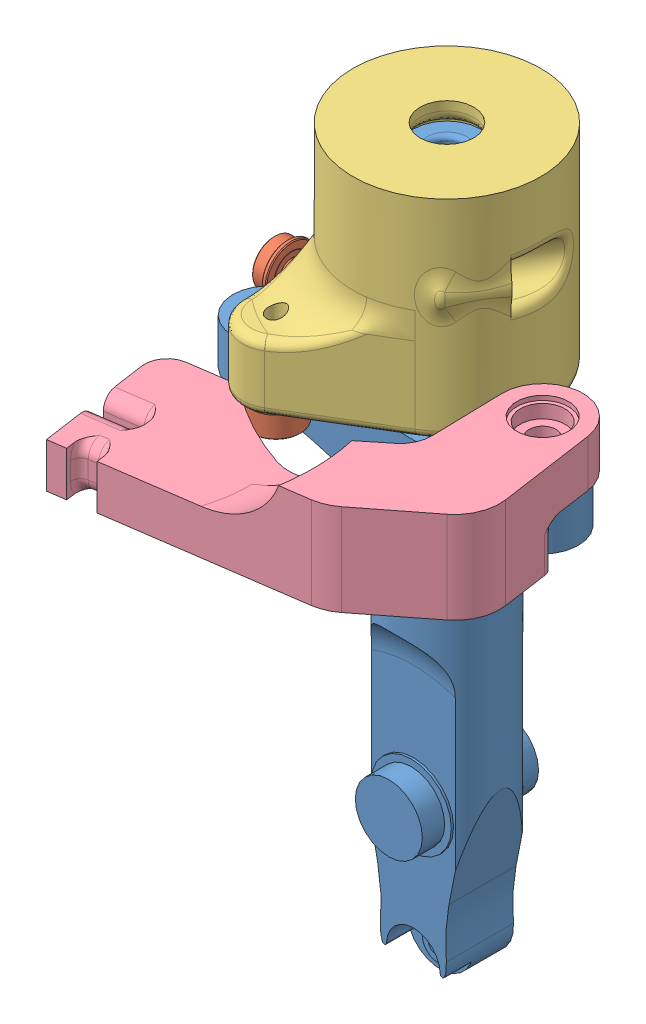
SolidWorks assembly Twist Assembly, configuration Default. Lengths in mm.
Overall size (93.92 163.27 87.75).
6 component instances, 4 part files, 9 mates.
Components (placement in the parent):
- Center Core-1: Center Core [Default] at (54.6829 0.4062 116.0872) size (77.28 158.27 34.47)
- Bearing-1: Bearing [685] at (40.6829 113.6785 140.3359) x (0 -1 0) z (-0.553847 0 0.832618) size (5 11 11)
- Twist-1: Twist [Default] at (54.6829 116.6785 116.0872) x (0.866025 0 0.5) z (-0.5 0 0.866025) size (43.41 47 56.5)
- Bearing-2: Bearing [6804] at (54.6829 120.1785 116.0872) x (0 1 0) z (0 0 1) size (7 32 32)
- CAM Twist-1: CAM Twist [Default] at (85.3215 126.6785 125.3217) x (0.989772 0 -0.142661) z (-0.142661 0 -0.989772) size (76.94 21.7 49.19)
- Bearing-3: Bearing [MF105] at (8.0433 107.4625 106.1073) size (4 11.6 11.6)
Mates (geometry in assembly coordinates):
- Concentric1: concentric anti-aligned: cylinder of Center Core-1 through (54.6829 89.2322 116.0872) axis (0 1 0) radius 10; cylinder of Bearing-2 through (54.6829 110.5999 116.0872) axis (0 -1 0) radius 10
- Coincident1: coincident anti-aligned: plane of Center Core-1 through (54.6829 116.6785 126.0872) normal (0 1 0); plane of Bearing-2 through (43.2829 116.6785 116.0872) normal (0 -1 0)
- Concentric2: concentric anti-aligned: cylinder of Center Core-1 through (54.6829 93.6785 116.0872) axis (0 1 0) radius 17.2345; cylinder of Twist-1 through (54.6829 116.6785 116.0872) axis (0 -1 0) radius 16
- Coincident2: coincident aligned: plane of Twist-1 through (46.6829 116.6785 129.9436) normal (0 -1 0); plane of Bearing-2 through (38.6829 116.6785 116.0872) normal (0 -1 0)
- Concentric3: concentric anti-aligned: cylinder of Bearing-1 through (40.6829 123.2572 140.3359) axis (0 1 0) radius 2.5; cylinder of Twist-1 through (40.6829 131.6785 140.3359) axis (0 -1 0) radius 2
- Distance2: distance = 0.5 mm anti-aligned: plane of CAM Twist-1 through (85.3215 116.1785 125.3217) normal (0 -1 0); plane of Center Core-1 through (54.6829 115.6785 127.5872) normal (0 1 0)
- LimitAngle1: limit planar angle = 1.047198 rad aligned: plane of Twist-1 through (54.6829 116.6785 116.0872) normal (0.866025 0 0.5)
- PathMate2: path: point of Bearing-1; curve of CAM Twist-1; curve of CAM Twist-1
- Concentric5: concentric aligned: cylinder of Center Core-1 through (85.3215 93.6785 125.3217) axis (0 1 0) radius 8; cylinder of CAM Twist-1 through (85.3215 106.1785 125.3217) axis (0 1 0) radius 9
